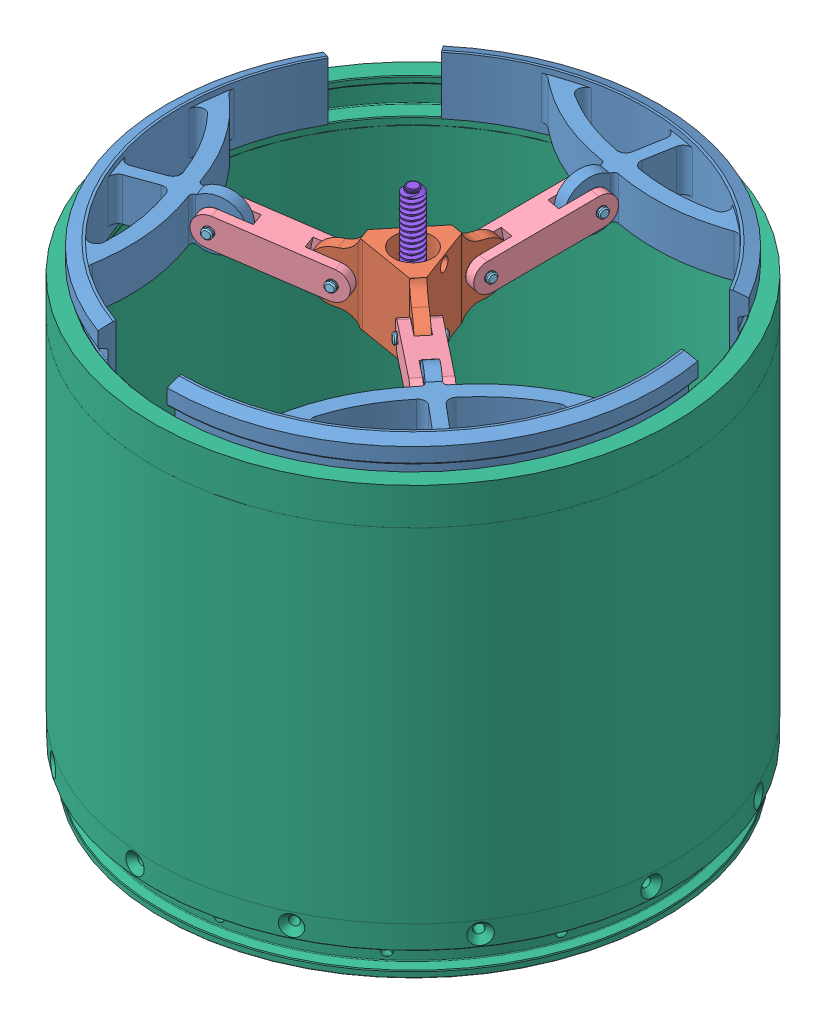
SolidWorks assembly Complete_Assembly, configuration Default. Lengths in mm.
Overall size (235.13 166.19 235.13).
29 component instances, 11 part files, 2 mates.
Components (placement in the parent):
- Upper_Ring_Carriage_Clamps-1: Upper_Ring_Carriage_Clamps [Default] at (25.8796 8.3221 57.7646) size (196.47 29.88 195.11)
  - Clamp_Ring_Concept-1: Clamp_Ring_Concept [Default] at (-27.5623 8.2477 38.9578) size (92.15 21.41 97.73)
  - Ring_Concept-1: Ring_Concept [Default] at (-27.5623 8.3392 38.9578) size (167.64 21.41 167.64) (hidden)
  - Clamp_Ring_Concept-2: Clamp_Ring_Concept [Default] at (45.0279 8.2477 -86.7722) x (-0.5 0 -0.866025) z (0.866025 0 -0.5) size (92.15 21.41 97.73)
  - Clamp_Ring_Concept-3: Clamp_Ring_Concept [Default] at (-100.1526 8.2477 -86.7722) x (-0.5 0 0.866025) z (-0.866025 0 -0.5) size (92.15 21.41 97.73)
  - Carriage-1: Carriage [Default] at (-27.5623 -9.5323 -44.8622) x (0.936847 0 -0.349739) z (0.349739 0 0.936847) size (41.67 25.4 47.99)
  - Bearing_RMA-1: Bearing_RMA [2342K61] at (-74.0304 8.8117 -27.7924) x (0.939693 0 -0.34202) z (0.34202 0 0.939693) size (9.53 9.53 3.97)
  - Linkage-2: Linkage [Default] at (0.06 0 -0.0715) size (38.12 15.04 34.41)
  - Bearing_RMA-2: Bearing_RMA [2342K61] at (10.4545 8.8117 -13.1545) x (-0.766044 0 -0.642788) z (0.642788 0 -0.766044) size (9.53 9.53 3.97)
  - Bearing_RMA-3: Bearing_RMA [2342K61] at (-19.1111 8.8117 -93.6395) x (-0.173648 0 0.984808) z (-0.984808 0 -0.173648) size (9.53 9.53 3.97)
  - Bearing_RMA-4: Bearing_RMA [2342K61] at (-44.5111 3.1677 -38.5376) x (0.939693 0 -0.34202) z (0.34202 0 0.939693) size (9.53 9.53 3.97)
  - Bearing_RMA-5: Bearing_RMA [2342K61] at (-13.6107 3.1677 -33.3464) x (-0.766044 0 -0.642788) z (0.642788 0 -0.766044) size (9.53 9.53 3.97)
  - Bearing_RMA-6: Bearing_RMA [2342K61] at (-24.5651 3.1677 -62.7025) x (-0.173648 0 0.984808) z (-0.984808 0 -0.173648) size (9.53 9.53 3.97)
  - Linkage-3: Linkage [Default] at (-2.5836 0 -91.1791) x (-0.5 0 -0.866025) z (0.866025 0 -0.5) size (38.12 15.04 34.41)
  - Linkage-4: Linkage [Default] at (-80.1633 0 -43.3359) x (-0.5 0 0.866025) z (-0.866025 0 -0.5) size (38.12 15.04 34.41)
  - Dowell_Pin_1-1: Dowell_Pin_1 [Default] at (-19.1831 8.8117 -93.6522) x (0.030154 0.984808 -0.17101) z (-0.17101 0.173648 0.969846) size (3.17 13.21 3.17)
  - Dowell_Pin_1-2: Dowell_Pin_1 [Default] at (-24.6381 3.1677 -62.7154) x (0.030154 0.984808 -0.17101) z (-0.17101 0.173648 0.969846) size (3.17 13.21 3.17)
  - Dowell_Pin_1-3: Dowell_Pin_1 [Default] at (-44.4858 3.1677 -38.468) x (-0.163176 0.984808 0.059391) z (0.925417 0.173648 -0.336824) size (3.17 13.21 3.17)
  - Dowell_Pin_1-4: Dowell_Pin_1 [Default] at (-13.5631 3.1677 -33.4031) x (0.133022 0.984808 0.111619) z (-0.754407 0.173648 -0.633022) size (3.17 13.21 3.17)
  - Dowell_Pin_1-5: Dowell_Pin_1 [Default] at (-74.0054 8.8117 -27.7238) x (-0.163176 0.984808 0.059391) z (0.925417 0.173648 -0.336824) size (3.17 13.21 3.17)
  - Dowell_Pin_1-6: Dowell_Pin_1 [Default] at (10.5015 8.8117 -13.2105) x (0.133022 0.984808 0.111619) z (-0.754407 0.173648 -0.633022) size (3.17 13.21 3.17)
- Lower_Ring_REF_Assem-1: Lower_Ring_REF_Assem [Default] at (-20.6232 -94.5117 1.5206) x (-0.825405 0 -0.56454) z (0.56454 0 -0.825405) size (169.16 166.19 169.16)
  - Lower_Ring-1: Lower_Ring [Default] at (-22.0591 -19.4905 1.2981) size (169.16 141.12 169.16)
  - Motor1_small-1: Motor1_small [Default] at (-22.0591 28.0936 1.2981) x (0 1 0) z (0.475154 0 0.879902) size (67.95 37.34 37.34)
  - ACME_Screw-1: ACME_Screw [Default] at (-22.0591 66.2345 1.2981) x (0 -1 0) z (0 0 1) size (70.01 6.35 6.51)
  - 0.125_0.5_Coupler-1: 0.125_0.5_Coupler [Default] at (-20.3654 55.2004 -13.8829) x (0.950754 0 0.309947) z (-0.309947 0 0.950754) size (11.98 13.97 10.67)
    - 0.125_0.5_Coupler-1: 0.125_0.5_Coupler [Default] at (3.095 2.7029 14.9583) size (10.67 13.97 10.67)
    - 97705A142-1: 97705A142 [97705A142] at (7.3322 12.9938 14.9389) x (-0.004504 -0.175182 -0.984526) z (0.99999 0 -0.004574) size (2.52 2.21 4.96)
    - 97705A142-2: 97705A142 [97705A142] at (6.8507 6.382 14.9411) x (-0.000926 -0.979309 -0.202367) z (0.99999 0 -0.004574) size (2.52 2.21 4.96)
Mates (geometry in assembly coordinates):
- Concentric1: concentric: cylinder of Upper_Ring_Carriage_Clamps-1/Ring_Concept-1 through (-1.6827 22.6662 12.9024) axis (0 -1 0) radius 80.82; cylinder of Lower_Ring_REF_Assem-1/Lower_Ring-1 through (-1.6827 -117.7432 12.9024) axis (0 -1 0) radius 81.5769
- Coincident1: coincident: plane of Upper_Ring_Carriage_Clamps-1/Ring_Concept-1 through (-1.6827 16.6613 91.3489) normal (0 -1 0); plane of Lower_Ring_REF_Assem-1/Lower_Ring-1 through (-46.3962 16.6613 78.2773) normal (0 1 0)
